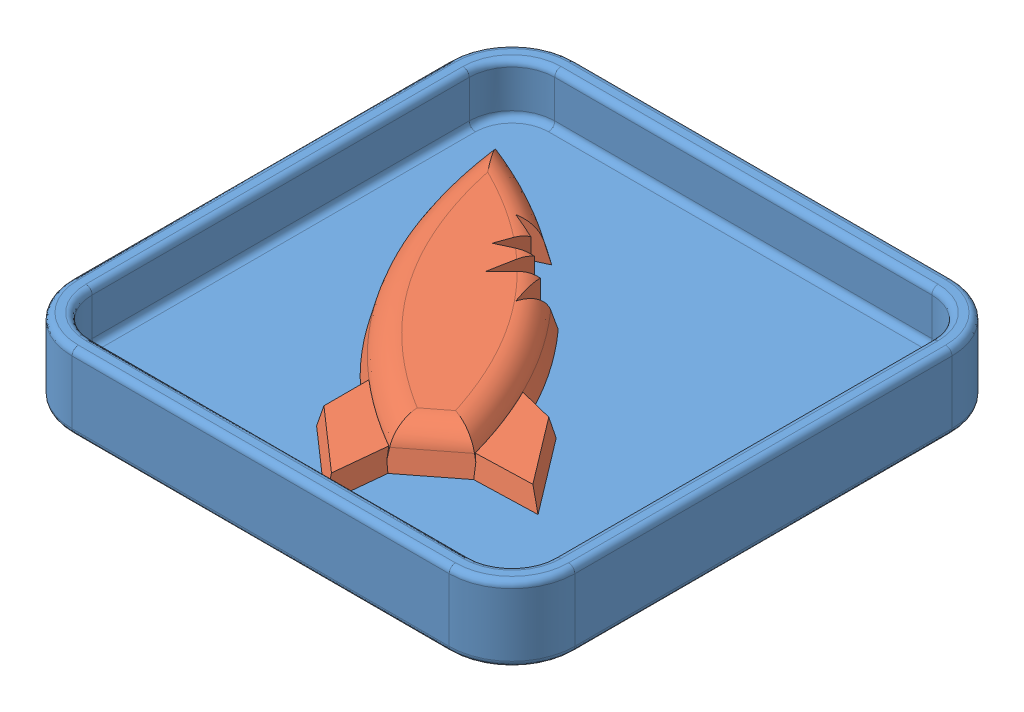
SolidWorks assembly Salvage, configuration Default. Lengths in mm.
Overall size (40 6 40).
2 component instances, 2 part files, 2 mates.
Components (placement in the parent):
- Tile-1: Tile [Default] at (13.198 18.4829 31.2043) size (40 6 40)
- SalvageExplorer-1: SalvageExplorer [Default] at (13.0921 20.4829 30.8043) size (27.3 3.68 30.06)
Mates (geometry in assembly coordinates):
- Coincident1: coincident anti-aligned: plane of Tile-1 through (-1.802 20.4829 46.2043) normal (0 1 0); plane of SalvageExplorer-1 through (13.0921 20.4829 30.8043) normal (0 -1 0)
- Coincident2: coincident anti-aligned: line of Tile-1 through (28.198 20.4829 13.3043) axis (-1 0 0); line of SalvageExplorer-1 through (-4.4079 20.4829 13.3043) axis (1 0 0)
